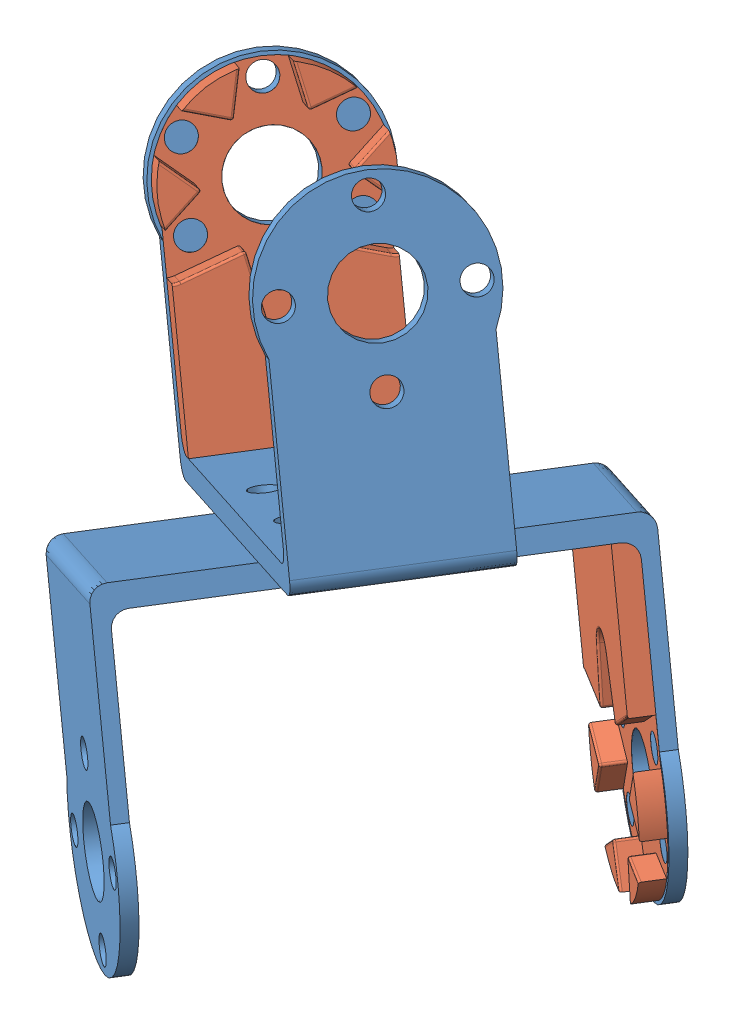
SolidWorks assembly box3_90_right_supplement, configuration Predeterminado. Lengths in mm.
Overall size (85.69 98.73 75.62).
4 component instances, 2 part files, 8 mates.
Components (placement in the parent):
- u_bracket-1: u_bracket [Predeterminado] at (132.1357 -74.2778 -18.2854) x (0.773259 0.381087 0.506798) z (-0.543971 -0.012024 0.839018) size (60 44.22 26.36)
- u_bracket-2: u_bracket [Predeterminado] at (132.7874 -76.1267 -17.8894) x (-0.543971 -0.012024 0.839018) z (0.773259 0.381087 0.506798) size (60 44.22 26.36)
- supplement_u_f_horn-2: supplement_u_f_horn [Predeterminado] at (157.8066 -103.5608 -35.4339) x (0.325832 -0.924461 0.198002) z (-0.773259 -0.381087 -0.506798) size (40.74 3.02 25.4)
- supplement_u_f_horn-3: supplement_u_f_horn [Predeterminado] at (100.6965 -57.1774 -38.4237) x (-0.325832 0.924461 -0.198002) z (0.543971 0.012024 -0.839018) size (40.74 3.02 25.4)
Mates (geometry in assembly coordinates):
- Coincidente16: coincident anti-aligned: plane of u_bracket-1 through (132.4616 -75.2022 -18.0874) normal (0.325832 -0.924461 0.198002); plane of u_bracket-2 through (132.4616 -75.2022 -18.0874) normal (-0.325832 0.924461 -0.198002)
- Concéntrica55: concentric anti-aligned: cylinder of u_bracket-1 through (118.0529 -34.3216 -26.8432) axis (0.325832 -0.924461 0.198002) radius 5.4; cylinder of u_bracket-2 through (146.8702 -116.0828 -9.3315) axis (-0.325832 0.924461 -0.198002) radius 5.4
- Paralelo2: parallel aligned: plane of u_bracket-1 through (101.7587 -84.0057 -23.8171) normal (-0.543971 -0.012024 0.839018); plane of u_bracket-2 through (107.8408 -82.9094 1.5956) normal (-0.543971 -0.012024 0.839018)
- Coincidente18: coincident anti-aligned: cylinder of u_bracket-2 through (157.8066 -103.5608 -35.4339) axis (0.543971 0.012024 -0.839018) radius 5.3; circle of supplement_u_f_horn-2
- Coincidente19: coincident anti-aligned: plane of u_bracket-2 through (157.8066 -103.5608 -35.4339) normal (-0.543971 -0.012024 0.839018); plane of supplement_u_f_horn-2 through (157.8066 -103.5608 -35.4339) normal (0.543971 0.012024 -0.839018)
- Coincidente20: coincident aligned: plane of u_bracket-2 through (140.4791 -82.1879 -48.7455) normal (-0.773259 -0.381087 -0.506798); plane of supplement_u_f_horn-2 through (137.7592 -82.2481 -44.5504) normal (-0.773259 -0.381087 -0.506798)
- Coincidente21: coincident aligned: circle of u_bracket-1; circle of supplement_u_f_horn-3
- Coincidente22: coincident aligned: plane of u_bracket-1 through (101.7587 -84.0057 -23.8171) normal (-0.543971 -0.012024 0.839018); plane of supplement_u_f_horn-3 through (105.625 -82.1003 -21.2831) normal (-0.543971 -0.012024 0.839018)
